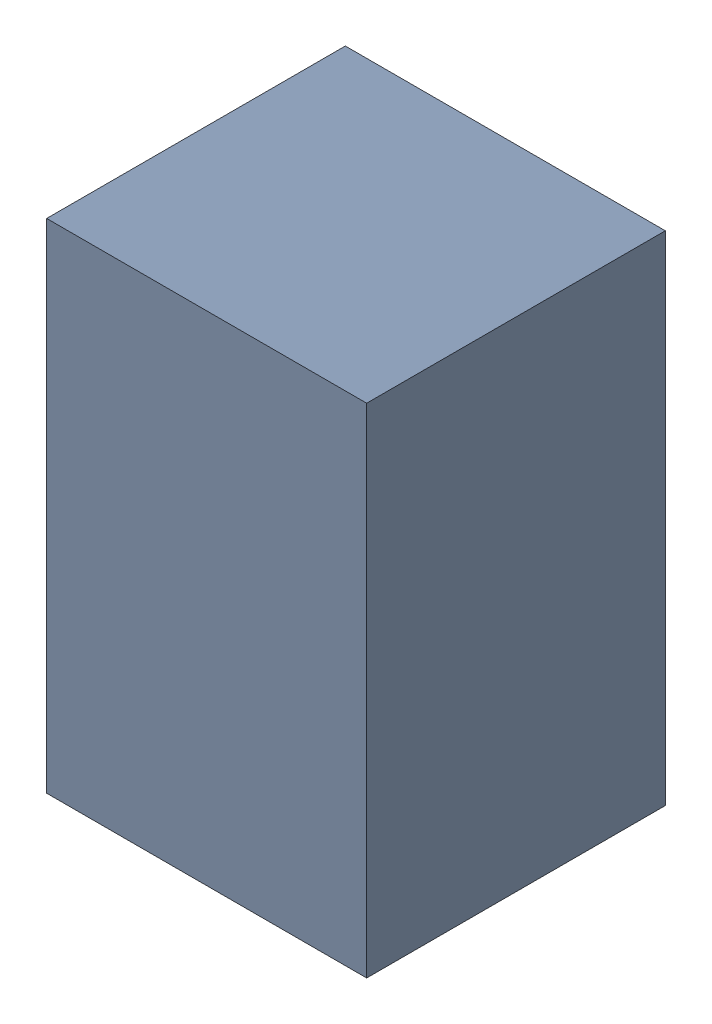
SolidWorks assembly CL3, configuration Default. Lengths in mm.
Overall size (1.35 2.1 1.26).
2 component instances, 1 part files, 0 mates.
Components (placement in the parent):
- 407985696-1: 407985696 [Default] at (30.988 34.163 0.0127) size (1.35 2.1 1.26)
  - Extruded_1-1: Extruded_1 [Default] at origin size (1.35 2.1 1.26)
